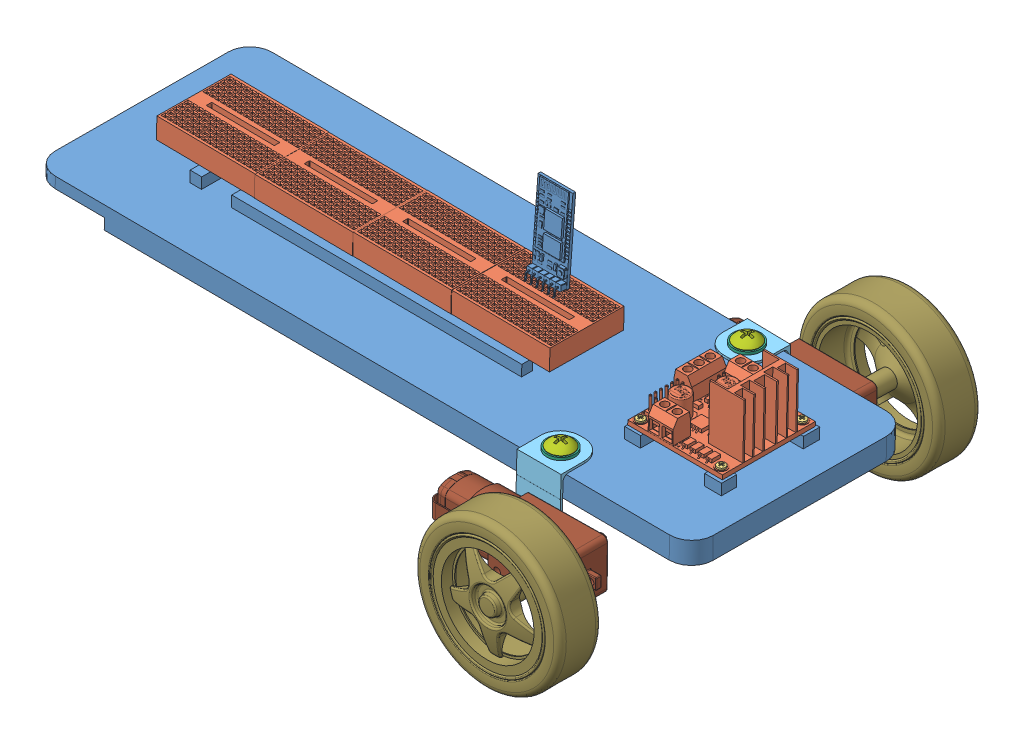
SolidWorks assembly Ensamblaje plataforma, configuration Default. Lengths in mm.
Overall size (300.76 111.34 196.85).
51 component instances, 20 part files, 63 mates.
Components (placement in the parent):
- Assem2^Ensamblaje plataforma-1: Assem2^Ensamblaje plataforma [Default] at (0.7866 12.6828 -10.4921) x (0.999913 -0.011798 -0.005953) z (0.006078 0.010581 0.999926) size (300 15 100) (virtual)
  - Plataforma base-1: Plataforma base [Default] at (153.6211 143.2192 210.7445) size (300 15 100)
- L298N Stepper Motor Driver (Red)-Part File_1-1: L298N Stepper Motor Driver (Red)-Part File_1 [Default] at (301.9412 169.4314 181.3452) x (0.008999 0.010546 0.999904) z (-0.999891 0.011828 0.008874) size (43 28.01 43)
- binding head screw_ai-7: binding head screw_ai [CR-BHMS 0.073-64x0.5625x0.5625-N] at (283.2565 172.6942 162.734) x (-0.011734 -0.999874 0.010651) z (0.010981 0.010523 0.999884) size (20.07 3.89 3.89)
- binding head screw_ai-8: binding head screw_ai [CR-BHMS 0.073-64x0.5625x0.5625-N] at (283.5929 173.0884 200.1099) x (-0.011734 -0.999874 0.010651) z (0.010981 0.010523 0.999884) size (20.07 3.89 3.89)
- binding head screw_ai-9: binding head screw_ai [CR-BHMS 0.073-64x0.5625x0.5625-N] at (320.3307 172.6538 199.7838) x (-0.011734 -0.999874 0.010651) z (0.010981 0.010523 0.999884) size (20.07 3.89 3.89)
- binding head screw_ai-10: binding head screw_ai [CR-BHMS 0.073-64x0.75x0.75-N] at (319.9943 172.2596 162.4079) x (-0.011734 -0.999874 0.010651) z (0.010981 0.010523 0.999884) size (20.07 3.89 3.89)
- machine screw nut hex_ai-2: machine screw nut hex_ai [MSHXNUT 0.073-64-S-N] at (283.5658 170.7773 200.1345) x (0.99987 -0.011614 0.011203) z (-0.011734 -0.999874 0.010651) size (3.96 4.58 1.27)
- machine screw nut hex_ai-4: machine screw nut hex_ai [MSHXNUT 0.073-64-S-N] at (283.3423 151.7297 200.3374) x (0.99987 -0.011614 0.011203) z (-0.011734 -0.999874 0.010651) size (3.96 4.58 1.27)
- machine screw nut hex_ai-5: machine screw nut hex_ai [MSHXNUT 0.073-64-S-N] at (320.6313 153.1446 200.5515) x (0.99987 -0.011614 0.011203) z (-0.011734 -0.999874 0.010651) size (3.96 4.58 1.27)
- machine screw nut hex_ai-6: machine screw nut hex_ai [MSHXNUT 0.073-64-S-N] at (319.939 167.5488 162.4581) x (0.99987 -0.011614 0.011203) z (-0.011734 -0.999874 0.010651) size (3.96 4.58 1.27)
- machine screw nut hex_ai-7: machine screw nut hex_ai [MSHXNUT 0.073-64-S-N] at (320.5829 152.7393 162.4434) x (0.99987 -0.011614 0.011203) z (-0.011734 -0.999874 0.010651) size (3.96 4.58 1.27)
- machine screw nut hex_ai-8: machine screw nut hex_ai [MSHXNUT 0.073-64-S-N] at (283.0059 151.3355 162.9615) x (0.99987 -0.011614 0.011203) z (-0.011734 -0.999874 0.010651) size (3.96 4.58 1.27)
- L bracket-1: L bracket [fillet] at (261.7617 166.8658 234.9781) x (-0.011734 -0.999874 0.010651) z (0.99985 -0.011868 -0.012638) size (40 20 20)
- L bracket-2: L bracket [fillet] at (281.5806 165.4754 129.2207) x (-0.011734 -0.999874 0.010651) z (-0.999906 0.011657 -0.007263) size (40 20 20)
- flat washer type a selected narrow_ai-3: flat washer type a selected narrow_ai [Selected Narrow FW 0.25] at (271.6351 166.6417 224.8168) x (-0.011734 -0.999874 0.010651) z (-0.01136 0.010785 0.999877) size (1.24 12.7 12.7)
- flat washer type a selected narrow_ai-4: flat washer type a selected narrow_ai [Selected Narrow FW 0.25] at (271.5069 165.6998 139.1835) x (-0.011734 -0.999874 0.010651) z (-0.01136 0.010785 0.999877) size (1.24 12.7 12.7)
- truss head screw_ai-5: truss head screw_ai [CR-THMS 0.19-24x0.75x0.75-N] at (271.6848 170.883 224.7716) x (-0.011734 -0.999874 0.010651) z (-0.01136 0.010785 0.999877) size (22 11.38 11.38)
- truss head screw_ai-6: truss head screw_ai [CR-THMS 0.19-24x0.75x0.75-N] at (271.5567 169.941 139.1383) x (-0.011734 -0.999874 0.010651) z (-0.01136 0.010785 0.999877) size (22 11.38 11.38)
- flat washer type b regular_ai-5: flat washer type b regular_ai [Regular FW 0.086] at (271.0581 131.529 130.5102) x (0.007138 -0.010736 -0.999917) z (0.999909 -0.011365 0.00726) size (0.81 6.35 6.35)
- flat washer type b regular_ai-6: flat washer type b regular_ai [Regular FW 0.086] at (271.2717 149.7347 130.3162) x (0.007138 -0.010736 -0.999917) z (0.999909 -0.011365 0.00726) size (0.81 6.35 6.35)
- flat washer type b wide_ai-3: flat washer type b wide_ai [Wide FW 0.086] at (274.1118 143.1002 233.7268) x (0.008955 0.011258 0.999897) z (-0.999897 -0.011157 0.00908) size (0.81 8.74 8.74)
- flat washer type b wide_ai-4: flat washer type b wide_ai [Wide FW 0.086] at (271.4602 132.657 233.9126) x (0.012763 0.010502 0.999863) z (-0.999855 -0.011115 0.01288) size (0.81 8.74 8.74)
- hex jam nut_ai-2: hex jam nut_ai [HJNUT 0.2500-20-D-N] at (271.4528 151.1115 224.9822) x (0.999876 -0.011621 0.010593) z (-0.011734 -0.999874 0.010651) size (11.11 12.83 4.14)
- hex jam nut_ai-3: hex jam nut_ai [HJNUT 0.2500-20-D-N] at (271.3251 150.2007 139.3486) x (0.999876 -0.011621 0.010593) z (-0.011734 -0.999874 0.010651) size (11.11 12.83 4.14)
- Moto Reductor - Rueda-1: Moto Reductor - Rueda [Predeterminado] at (332.6461 144.5484 56.2291) x (0.999975 0.000031 0.007138) z (-0.007138 0.010736 0.999917) size (86.5 66 53.9)
  - Moto Reductor 01-1: Moto Reductor 01 [Predeterminado] at (-77.2566 -5.0689 64.1747) size (69.7 22.5 36.8)
  - Rueda 01-2: Rueda 01 [Predeterminado] at (-40.4566 -5.0689 48.6747) x (0 0 -1) z (1 0 0) size (25 66 66)
- Moto Reductor - Rueda-2: Moto Reductor - Rueda [Predeterminado] at (333.4674 137.1162 307.96) x (0.999919 -0.000131 -0.012762) z (-0.012763 -0.010502 -0.999863) size (86.5 66 53.9)
  - Moto Reductor 01-1: Moto Reductor 01 [Predeterminado] at (-77.2566 -5.0689 64.1747) size (69.7 22.5 36.8)
  - Rueda 01-2: Rueda 01 [Predeterminado] at (-40.4566 -5.0689 48.6747) x (0 0 -1) z (1 0 0) size (25 66 66)
- Ensamble_Rueda_Loca-2: Ensamble_Rueda_Loca [Predeterminado] at (113.0575 150.5663 140.703) x (0.988318 -0.001958 -0.152395) z (0.15239 -0.002472 0.988317) size (50.13 42.44 33)
  - Base_rueda_loca-1: Base_rueda_loca [Predeterminado] at (0.7239 4.3377 41.0399) size (41.04 4 33)
  - rueda loca-1: rueda loca [Predeterminado] at (0.7239 -3.6623 41.0399) x (0.15258 0 -0.988291) z (0.988291 0 0.15258) size (23.5 25.74 27.45)
  - Llanta-1: Llanta [Predeterminado] at (12.3641 -17.7732 42.8347) x (0.152548 0.020285 -0.988088) z (0.775985 0.616686 0.132462) size (12.69 24.5 24.5)
  - Eje_planta-1: Eje_planta [Predeterminado] at (10.931 -17.9637 52.1172) x (0.152548 0.020285 -0.988088) z (0.959429 -0.242914 0.143137) size (19.4 6 6)
  - Pasante_Base-1: Pasante_Base [Predeterminado] at (0.7239 4.3377 41.0399) size (7 3 7)
- truss head screw_ai-10: truss head screw_ai [CR-THMS 0.086-64x0.75x0.75-N] at (136.8159 167.6021 170.7576) x (-0.011734 -0.999874 0.010651) z (-0.011356 0.010785 0.999877) size (15.6 4.93 4.93)
- truss head screw_ai-11: truss head screw_ai [CR-THMS 0.086-64x0.75x0.75-N] at (137.0547 167.8615 195.3686) x (-0.011734 -0.999874 0.010651) z (-0.011356 0.010785 0.999877) size (15.6 4.93 4.93)
- truss head screw_ai-12: truss head screw_ai [CR-THMS 0.086-64x0.5625x0.5625-N] at (107.7869 168.2045 195.3265) x (-0.011734 -0.999874 0.010651) z (-0.011356 0.010785 0.999877) size (15.6 4.93 4.93)
- truss head screw_ai-13: truss head screw_ai [CR-THMS 0.086-64x0.75x0.75-N] at (107.6388 167.9466 170.955) x (-0.011734 -0.999874 0.010651) z (-0.011356 0.010785 0.999877) size (15.6 4.93 4.93)
- hex nut style 1 gradeab_bsi-9: hex nut style 1 gradeab_bsi [BS EN 24032 - M2.5 - W - N] at (107.4319 150.3152 171.1429) x (0.999871 -0.011616 0.011069) z (-0.011734 -0.999874 0.010651) size (5 5.77 2)
- hex nut style 1 gradeab_bsi-10: hex nut style 1 gradeab_bsi [BS EN 24032 - M2.5 - W - N] at (107.58 150.5731 195.5143) x (0.999871 -0.011616 0.011069) z (-0.011734 -0.999874 0.010651) size (5 5.77 2)
- hex nut style 1 gradeab_bsi-11: hex nut style 1 gradeab_bsi [BS EN 24032 - M2.5 - W - N] at (136.8478 150.23 195.5564) x (0.999871 -0.011616 0.011069) z (-0.011734 -0.999874 0.010651) size (5 5.77 2)
- hex nut style 1 gradeab_bsi-12: hex nut style 1 gradeab_bsi [BS EN 24032 - M2.5 - W - N] at (136.609 149.9707 170.9455) x (0.999871 -0.011616 0.011069) z (-0.011734 -0.999874 0.010651) size (5 5.77 2)
- HC-05-1: HC-05 [Default] at (216.0062 199.2394 171.712) x (0.000557 -0.996765 0.080373) z (-0.999999 -0.000623 -0.00079) size (42.58 6.55 16)
- protoboard1-1: protoboard1 [Default] at (57.3322 157.7537 151.7303) x (0.999931 -0.011734 0.000062) z (0.000062 0.010651 0.999943) size (180 9.71 34.34)
  - MINIPROTOBOARD-1: MINIPROTOBOARD [Default] at (27.1001 14.4376 32.0233) size (45 9.5 34)
  - MINIPROTOBOARD-2: MINIPROTOBOARD [Default] at (72.1001 14.3685 32.1136) size (45 9.5 34)
  - MINIPROTOBOARD-3: MINIPROTOBOARD [Default] at (162.1001 14.231 31.7752) size (45 9.5 34)
  - MINIPROTOBOARD-4: MINIPROTOBOARD [Default] at (117.1001 14.3838 31.9917) size (45 9.5 34)
Mates (geometry in assembly coordinates):
- Concentric2: concentric: cylinder of assembly; circle of assembly; cylinder of Assem2^Ensamblaje plataforma-1/Plataforma base-1 through (281.9865 64.4664 163.8869) axis (0.011734 0.999874 -0.010651) radius 1.8; circle of L298N Stepper Motor Driver (Red)-Part File_1-1
- Concentric7: concentric: cylinder of assembly; cylinder of assembly; cylinder of L298N Stepper Motor Driver (Red)-Part File_1-1 through (283.2162 169.2533 162.7706) axis (0.011734 0.999874 -0.010651) radius 1.75; cylinder of binding head screw_ai-7 through (283.5546 198.091 162.4634) axis (0.011734 0.999874 -0.010651) radius 0.9271
- Coincident22: coincident: plane of assembly; plane of assembly; plane of L298N Stepper Motor Driver (Red)-Part File_1-1 through (285.7513 171.5964 160.1929) normal (0.011734 0.999874 -0.010651); plane of binding head screw_ai-7 through (284.1713 171.642 162.735) normal (-0.011734 -0.999874 0.010651)
- Concentric8: concentric: cylinder of assembly; cylinder of assembly; cylinder of L298N Stepper Motor Driver (Red)-Part File_1-1 through (283.5525 169.6475 200.1466) axis (0.011734 0.999874 -0.010651) radius 1.75; cylinder of binding head screw_ai-8 through (283.891 198.4853 199.8393) axis (0.011734 0.999874 -0.010651) radius 0.9271
- Coincident23: coincident: plane of assembly; plane of assembly; plane of L298N Stepper Motor Driver (Red)-Part File_1-1 through (286.0877 171.9906 197.5688) normal (0.011734 0.999874 -0.010651); plane of binding head screw_ai-8 through (284.5077 172.0362 200.1109) normal (-0.011734 -0.999874 0.010651)
- Concentric9: concentric: cylinder of assembly; cylinder of assembly; cylinder of L298N Stepper Motor Driver (Red)-Part File_1-1 through (320.2903 169.2129 199.8205) axis (0.011734 0.999874 -0.010651) radius 1.75; cylinder of binding head screw_ai-9 through (320.6287 198.0507 199.5133) axis (0.011734 0.999874 -0.010651) radius 0.9271
- Coincident24: coincident: plane of assembly; plane of assembly; plane of L298N Stepper Motor Driver (Red)-Part File_1-1 through (322.8254 171.556 197.2427) normal (0.011734 0.999874 -0.010651); plane of binding head screw_ai-9 through (321.2455 171.6016 199.7849) normal (-0.011734 -0.999874 0.010651)
- Concentric10: concentric: cylinder of assembly; cylinder of assembly; cylinder of L298N Stepper Motor Driver (Red)-Part File_1-1 through (319.9539 168.8187 162.4446) axis (0.011734 0.999874 -0.010651) radius 1.75; cylinder of binding head screw_ai-10 through (320.2924 197.6564 162.1374) axis (0.011734 0.999874 -0.010651) radius 0.9271
- Coincident25: coincident: plane of assembly; plane of assembly; plane of L298N Stepper Motor Driver (Red)-Part File_1-1 through (322.4891 171.1618 159.8668) normal (0.011734 0.999874 -0.010651); plane of binding head screw_ai-10 through (320.9091 171.2074 162.409) normal (-0.011734 -0.999874 0.010651)
- Concentric111: concentric: cone of assembly; cylinder of assembly; cone of binding head screw_ai-8 through (283.5807 172.0472 200.121) axis (0.011734 0.999874 -0.010651); cylinder of machine screw nut hex_ai-2 through (283.8596 195.8117 199.8678) axis (-0.011734 -0.999874 0.010651) radius 0.9271
- Coincident261: coincident: plane of assembly; plane of assembly; plane of binding head screw_ai-8 through (284.5077 172.0362 200.1109) normal (-0.011734 -0.999874 0.010651); plane of machine screw nut hex_ai-2 through (283.5554 172.0718 202.4084) normal (0.011734 0.999874 -0.010651)
- Concentric12: concentric: cylinder of assembly; cylinder of assembly; cylinder of L298N Stepper Motor Driver (Red)-Part File_1-1 through (283.5525 169.6475 200.1466) axis (0.011734 0.999874 -0.010651) radius 1.75; cylinder of machine screw nut hex_ai-4 through (283.6361 176.7641 200.0707) axis (-0.011734 -0.999874 0.010651) radius 0.9271
- Coincident27: coincident: plane of assembly; plane of assembly; plane of binding head screw_ai-8 through (284.2842 152.9886 200.3138) normal (-0.011734 -0.999874 0.010651); plane of machine screw nut hex_ai-4 through (283.3318 153.0242 202.6113) normal (0.011734 0.999874 -0.010651)
- Concentric13: concentric: cylinder of assembly; cylinder of assembly; cylinder of Assem2^Ensamblaje plataforma-1/Plataforma base-1 through (319.5902 64.4258 201.4966) axis (0.011734 0.999874 -0.010651) radius 1.8; cylinder of machine screw nut hex_ai-5 through (320.9251 178.179 200.2848) axis (-0.011734 -0.999874 0.010651) radius 0.9271
- Coincident28: coincident: plane of assembly; plane of assembly; plane of Assem2^Ensamblaje plataforma-1/Plataforma base-1 through (157.3558 156.3015 197.7967) normal (-0.011734 -0.999874 0.010651); plane of machine screw nut hex_ai-5 through (320.6209 154.4392 202.8254) normal (0.011734 0.999874 -0.010651)
- Concentric14: concentric: cylinder of assembly; cylinder of assembly; cylinder of binding head screw_ai-10 through (320.2924 197.6564 162.1374) axis (0.011734 0.999874 -0.010651) radius 0.9271; cylinder of machine screw nut hex_ai-6 through (320.2328 192.5832 162.1914) axis (-0.011734 -0.999874 0.010651) radius 0.9271
- Coincident29: coincident: plane of assembly; plane of assembly; plane of L298N Stepper Motor Driver (Red)-Part File_1-1 through (317.4015 168.8219 159.9373) normal (-0.011734 -0.999874 0.010651); plane of machine screw nut hex_ai-6 through (319.9286 168.8433 164.732) normal (0.011734 0.999874 -0.010651)
- Concentric15: concentric: cylinder of assembly; cylinder of assembly; cylinder of Assem2^Ensamblaje plataforma-1/Plataforma base-1 through (319.5417 64.0204 163.3885) axis (0.011734 0.999874 -0.010651) radius 1.8; cylinder of machine screw nut hex_ai-7 through (320.8766 177.7736 162.1767) axis (-0.011734 -0.999874 0.010651) radius 0.9271
- Coincident30: coincident: plane of assembly; plane of assembly; plane of Assem2^Ensamblaje plataforma-1/Plataforma base-1 through (157.3558 156.3015 197.7967) normal (-0.011734 -0.999874 0.010651); plane of machine screw nut hex_ai-7 through (320.5724 154.0338 164.7173) normal (0.011734 0.999874 -0.010651)
- Concentric16: concentric: cylinder of assembly; cylinder of assembly; cylinder of L298N Stepper Motor Driver (Red)-Part File_1-1 through (283.2162 169.2533 162.7706) axis (0.011734 0.999874 -0.010651) radius 1.75; cylinder of machine screw nut hex_ai-8 through (283.2997 176.3699 162.6948) axis (-0.011734 -0.999874 0.010651) radius 0.9271
- Coincident31: coincident: plane of assembly; plane of assembly; plane of binding head screw_ai-7 through (283.9478 152.5944 162.9379) normal (-0.011734 -0.999874 0.010651); plane of machine screw nut hex_ai-8 through (282.9955 152.63 165.2354) normal (0.011734 0.999874 -0.010651)
- Concentric21: concentric: circle of assembly; circle of assembly; circle of Assem2^Ensamblaje plataforma-1/Plataforma base-1; circle of L bracket-1
- Coincident37: coincident: plane of assembly; line of assembly; plane of Assem2^Ensamblaje plataforma-1/Plataforma base-1 through (157.5318 171.2996 197.6369) normal (0.011734 0.999874 -0.010651); line of L298N Stepper Motor Driver (Red)-Part File_1-1 through (323.6324 169.4039 202.6524) axis (-0.999891 0.011828 0.008874)
- Concentric25: concentric: cylinder of assembly; circle of assembly; cylinder of Assem2^Ensamblaje plataforma-1/Plataforma base-1 through (271.139 134.3429 139.5175) axis (0.011734 0.999874 -0.010651) radius 5.0077; circle of L bracket-2
- Coincident42: coincident: plane of assembly; line of assembly; plane of Assem2^Ensamblaje plataforma-1/Plataforma base-1 through (157.5318 171.2996 197.6369) normal (0.011734 0.999874 -0.010651); line of L298N Stepper Motor Driver (Red)-Part File_1-1 through (323.6324 169.4039 202.6524) axis (-0.999891 0.011828 0.008874)
- Concentric281: concentric: cylinder of assembly; cylinder of assembly; cylinder of L bracket-1 through (271.5177 156.643 224.9233) axis (0.011734 0.999874 -0.010651) radius 5.0147; cylinder of flat washer type a selected narrow_ai-3 through (272.0449 201.5623 224.4448) axis (0.011734 0.999874 -0.010651) radius 3.175
- Coincident461: coincident: plane of assembly; plane of assembly; plane of L bracket-1 through (281.7587 166.6285 234.7253) normal (0.011734 0.999874 -0.010651); plane of flat washer type a selected narrow_ai-3 through (274.8096 166.6049 224.8532) normal (-0.011734 -0.999874 0.010651)
- Concentric29: concentric: cylinder of assembly; cylinder of assembly; cylinder of L bracket-2 through (271.3896 155.701 139.29) axis (0.011734 0.999874 -0.010651) radius 5.0147; cylinder of flat washer type a selected narrow_ai-4 through (271.9167 200.6204 138.8115) axis (0.011734 0.999874 -0.010651) radius 3.175
- Coincident47: coincident: plane of assembly; plane of assembly; plane of L bracket-2 through (261.5824 165.7086 129.0755) normal (0.011734 0.999874 -0.010651); plane of flat washer type a selected narrow_ai-4 through (274.6815 165.6629 139.22) normal (-0.011734 -0.999874 0.010651)
- Concentric31: concentric: cylinder of assembly; cylinder of assembly; cylinder of L bracket-1 through (271.5177 156.643 224.9233) axis (0.011734 0.999874 -0.010651) radius 5.0147; cylinder of truss head screw_ai-5 through (271.9829 196.2798 224.501) axis (0.011734 0.999874 -0.010651) radius 5.6896
- Coincident48: coincident: plane of assembly; plane of assembly; plane of flat washer type a selected narrow_ai-3 through (277.9988 167.8124 224.8764) normal (0.011734 0.999874 -0.010651); plane of truss head screw_ai-5 through (274.0623 167.8581 224.8312) normal (-0.011734 -0.999874 0.010651)
- Concentric32: concentric: cylinder of assembly; cylinder of assembly; cylinder of L bracket-2 through (271.3896 155.701 139.29) axis (0.011734 0.999874 -0.010651) radius 5.0147; cylinder of truss head screw_ai-6 through (271.8548 195.3378 138.8678) axis (0.011734 0.999874 -0.010651) radius 5.6896
- Coincident49: coincident: plane of assembly; plane of assembly; plane of flat washer type a selected narrow_ai-4 through (277.8707 166.8705 139.2432) normal (0.011734 0.999874 -0.010651); plane of truss head screw_ai-6 through (273.9342 166.9162 139.198) normal (-0.011734 -0.999874 0.010651)
- Concentric38: concentric: cylinder of assembly; cylinder of assembly; cylinder of L bracket-2 through (271.2722 131.2069 100.5127) axis (-0.007138 0.010736 0.999917) radius 1.5; cylinder of flat washer type b regular_ai-5 through (270.8088 131.9039 165.4323) axis (-0.007138 0.010736 0.999917) radius 1.1938
- Coincident55: coincident: plane of assembly; plane of assembly; plane of L bracket-2 through (261.5636 164.7194 130.086) normal (-0.007138 0.010736 0.999917); plane of flat washer type b regular_ai-5 through (271.0717 132.7226 130.4974) normal (0.007138 -0.010736 -0.999917)
- Concentric39: concentric: cylinder of assembly; cylinder of assembly; cylinder of L bracket-2 through (271.3431 149.6273 120.3171) axis (-0.007138 0.010736 0.999917) radius 1.5; cylinder of flat washer type b regular_ai-6 through (271.0224 150.1096 165.2383) axis (-0.007138 0.010736 0.999917) radius 1.1938
- Coincident56: coincident: plane of assembly; plane of assembly; plane of L bracket-2 through (261.5636 164.7194 130.086) normal (-0.007138 0.010736 0.999917); plane of flat washer type b regular_ai-6 through (271.2854 150.9283 130.3035) normal (0.007138 -0.010736 -0.999917)
- Concentric49: concentric: cylinder of assembly; cylinder of assembly; cylinder of Assem2^Ensamblaje plataforma-1/Plataforma base-1 through (271.2667 135.2537 225.1511) axis (0.011734 0.999874 -0.010651) radius 5.0077; cylinder of hex jam nut_ai-2 through (271.7466 176.1458 224.7155) axis (-0.011734 -0.999874 0.010651) radius 3.175
- Coincident66: coincident: plane of assembly; plane of assembly; plane of Assem2^Ensamblaje plataforma-1/Plataforma base-1 through (157.3558 156.3015 197.7967) normal (-0.011734 -0.999874 0.010651); plane of hex jam nut_ai-2 through (260.3903 155.3803 224.8204) normal (0.011734 0.999874 -0.010651)
- Concentric50: concentric: cylinder of assembly; cylinder of assembly; cylinder of Assem2^Ensamblaje plataforma-1/Plataforma base-1 through (271.139 134.3429 139.5175) axis (0.011734 0.999874 -0.010651) radius 5.0077; cylinder of hex jam nut_ai-3 through (271.6188 175.2351 139.0819) axis (-0.011734 -0.999874 0.010651) radius 3.175
- Coincident67: coincident: plane of assembly; plane of assembly; plane of Assem2^Ensamblaje plataforma-1/Plataforma base-1 through (157.3558 156.3015 197.7967) normal (-0.011734 -0.999874 0.010651); plane of hex jam nut_ai-3 through (260.2625 154.4695 139.1868) normal (0.011734 0.999874 -0.010651)
- Concentric282: concentric: circle of assembly; circle of assembly; circle of L bracket-1; circle of flat washer type b wide_ai-4
- Coincident473: coincident: circle of assembly; circle of assembly; circle of L bracket-2; circle of Moto Reductor - Rueda-1/Moto Reductor 01-1
- Coincident474: coincident: circle of assembly; circle of assembly; circle of L bracket-1; circle of Moto Reductor - Rueda-2/Moto Reductor 01-1
- Tangent1: tangent: curve of Assem2^Ensamblaje plataforma-1/Plataforma base-1; edge_curve of ?
- Concentric285: concentric: cylinder of assembly; cylinder of assembly; cylinder of Assem2^Ensamblaje plataforma-1/Plataforma base-1 through (136.2134 116.2624 171.3045) axis (0.011734 0.999874 -0.010651) radius 2.25; cylinder of truss head screw_ai-10 through (137.1139 192.999 170.4871) axis (0.011734 0.999874 -0.010651) radius 2.4638
- Coincident476: coincident: plane of assembly; plane of assembly; plane of Assem2^Ensamblaje plataforma-1/Plataforma base-1 through (157.4731 166.3003 197.6902) normal (0.011734 0.999874 -0.010651); plane of truss head screw_ai-10 through (137.8921 166.2434 170.7845) normal (-0.011734 -0.999874 0.010651)
- Concentric286: concentric: cylinder of assembly; cylinder of assembly; cylinder of Assem2^Ensamblaje plataforma-1/Plataforma base-1 through (136.9215 156.5167 195.4894) axis (0.011734 0.999874 -0.010651) radius 2.25; cylinder of truss head screw_ai-11 through (137.3527 193.2583 195.098) axis (0.011734 0.999874 -0.010651) radius 2.4638
- Coincident477: coincident: plane of assembly; plane of assembly; plane of Assem2^Ensamblaje plataforma-1/Plataforma base-1 through (157.4731 166.3003 197.6902) normal (0.011734 0.999874 -0.010651); plane of truss head screw_ai-11 through (138.1309 166.5028 195.3954) normal (-0.011734 -0.999874 0.010651)
- Concentric287: concentric: cylinder of assembly; cylinder of assembly; cylinder of Assem2^Ensamblaje plataforma-1/Plataforma base-1 through (107.1845 116.8648 195.8734) axis (0.011734 0.999874 -0.010651) radius 2.25; cylinder of truss head screw_ai-12 through (108.085 193.6013 195.056) axis (0.011734 0.999874 -0.010651) radius 2.4638
- Coincident478: coincident: plane of assembly; plane of assembly; plane of Assem2^Ensamblaje plataforma-1/Plataforma base-1 through (157.4731 166.3003 197.6902) normal (0.011734 0.999874 -0.010651); plane of truss head screw_ai-12 through (108.8632 166.8458 195.3534) normal (-0.011734 -0.999874 0.010651)
- Concentric288: concentric: cylinder of assembly; cylinder of assembly; cylinder of Assem2^Ensamblaje plataforma-1/Plataforma base-1 through (107.0363 116.6069 171.502) axis (0.011734 0.999874 -0.010651) radius 2.25; cylinder of truss head screw_ai-13 through (107.9368 193.3435 170.6845) axis (0.011734 0.999874 -0.010651) radius 2.4638
- Coincident479: coincident: plane of assembly; plane of assembly; plane of Assem2^Ensamblaje plataforma-1/Plataforma base-1 through (157.4731 166.3003 197.6902) normal (0.011734 0.999874 -0.010651); plane of truss head screw_ai-13 through (108.715 166.5879 170.9819) normal (-0.011734 -0.999874 0.010651)
- Concentric293: concentric: cylinder of assembly; cylinder of assembly; cylinder of truss head screw_ai-13 through (107.9368 193.3435 170.6845) axis (0.011734 0.999874 -0.010651) radius 1.0922; cylinder of hex nut style 1 gradeab_bsi-9 through (107.7257 175.3495 170.8762) axis (-0.011734 -0.999874 0.010651) radius 1.25
- Coincident486: coincident: plane of assembly; plane of assembly; plane of truss head screw_ai-13 through (108.5474 152.3022 171.1341) normal (-0.011734 -0.999874 0.010651); plane of hex nut style 1 gradeab_bsi-9 through (107.4238 152.346 174.008) normal (0.011734 0.999874 -0.010651)
- Concentric294: concentric: cylinder of assembly; cylinder of assembly; cylinder of truss head screw_ai-12 through (108.085 193.6013 195.056) axis (0.011734 0.999874 -0.010651) radius 1.0922; cylinder of hex nut style 1 gradeab_bsi-10 through (107.8738 175.6074 195.2477) axis (-0.011734 -0.999874 0.010651) radius 1.25
- Coincident487: coincident: plane of assembly; plane of assembly; plane of truss head screw_ai-12 through (108.6956 152.5601 195.5056) normal (-0.011734 -0.999874 0.010651); plane of hex nut style 1 gradeab_bsi-10 through (107.5719 152.6039 198.3795) normal (0.011734 0.999874 -0.010651)
- Concentric295: concentric: cylinder of assembly; cylinder of assembly; cylinder of truss head screw_ai-11 through (137.3527 193.2583 195.098) axis (0.011734 0.999874 -0.010651) radius 1.0922; cylinder of hex nut style 1 gradeab_bsi-11 through (137.1415 175.2644 195.2897) axis (-0.011734 -0.999874 0.010651) radius 1.25
- Coincident488: coincident: plane of assembly; plane of assembly; plane of truss head screw_ai-11 through (137.9633 152.2171 195.5476) normal (-0.011734 -0.999874 0.010651); plane of hex nut style 1 gradeab_bsi-11 through (136.8396 152.2609 198.4215) normal (0.011734 0.999874 -0.010651)
- Concentric296: concentric: cylinder of assembly; cylinder of assembly; cylinder of truss head screw_ai-10 through (137.1139 192.999 170.4871) axis (0.011734 0.999874 -0.010651) radius 1.0922; cylinder of hex nut style 1 gradeab_bsi-12 through (136.9028 175.005 170.6788) axis (-0.011734 -0.999874 0.010651) radius 1.25
- Coincident489: coincident: plane of assembly; plane of assembly; plane of truss head screw_ai-10 through (137.7245 151.9577 170.9367) normal (-0.011734 -0.999874 0.010651); plane of hex nut style 1 gradeab_bsi-12 through (136.6009 152.0015 173.8106) normal (0.011734 0.999874 -0.010651)
- Coincident494: coincident: plane of assembly; plane of assembly; plane of Assem2^Ensamblaje plataforma-1/Plataforma base-1 through (157.5318 171.2996 197.6369) normal (0.011734 0.999874 -0.010651); plane of protoboard1-1/MINIPROTOBOARD-3 through (219.59 170.4193 183.3622) normal (-0.011734 -0.999874 0.010651)
- Coincident495: coincident: line of assembly; plane of assembly; line of HC-05-1 through (209.6301 182.1149 178.1539) axis (0.000557 -0.996765 0.080373); plane of protoboard1-1/MINIPROTOBOARD-3 through (208.7961 179.4939 178.366) normal (0.000881 0.080373 0.996764)
